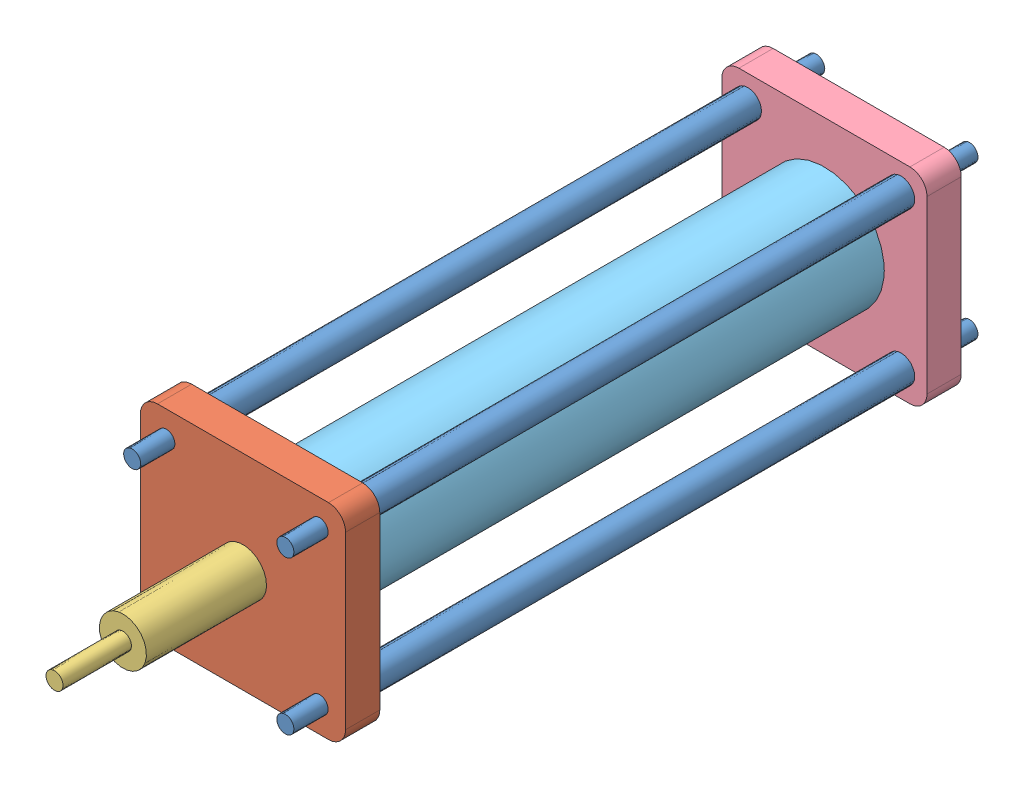
SolidWorks assembly E2_S4_AVA_E, configuration Default. Lengths in mm.
Overall size (76.2 76.2 311.28).
8 component instances, 5 part files, 16 mates.
Components (placement in the parent):
- E2_S4_AVA_P1-1: E2_S4_AVA_P1 [Default] at (10.7878 43.6934 193.1058) size (10.16 10.16 254)
- E2_S4_AVA_P2-1: E2_S4_AVA_P2 [Default] at (-17.6602 15.2454 294.7058) size (76.2 76.2 12.7)
- E2_S4_AVA_P3-1: E2_S4_AVA_P3 [Default] at (-17.6602 15.2454 136.0836) x (0.346747 0.937959 0) z (0 0 1) size (41.25 41.25 241.3)
- E2_S4_AVA_P4-1: E2_S4_AVA_P4 [Default] at (-17.6602 15.2454 78.8058) size (76.2 76.2 12.7)
- E2_S4_AVA_P5-1: E2_S4_AVA_P5 [Default] at (-17.6602 15.2454 91.5058) size (44.45 44.45 203.2)
- E2_S4_AVA_P1-2: E2_S4_AVA_P1 [Default] at (-46.1082 43.6934 193.1058) size (10.16 10.16 254)
- E2_S4_AVA_P1-3: E2_S4_AVA_P1 [Default] at (10.7878 -13.2026 193.1058) size (10.16 10.16 254)
- E2_S4_AVA_P1-4: E2_S4_AVA_P1 [Default] at (-46.1082 -13.2026 193.1058) size (10.16 10.16 254)
Mates (geometry in assembly coordinates):
- Concentric1: concentric aligned: cylinder of E2_S4_AVA_P1-1 through (10.7878 43.6934 320.1058) axis (0 0 -1) radius 3.175; cylinder of E2_S4_AVA_P2-1 through (10.7878 43.6934 307.4058) axis (0 0 -1) radius 3.175
- Coincident1: coincident anti-aligned: plane of E2_S4_AVA_P1-1 through (10.7878 43.6934 294.7058) normal (0 0 1); plane of E2_S4_AVA_P2-1 through (-49.4102 -16.5046 294.7058) normal (0 0 -1)
- Concentric2: concentric aligned: cylinder of E2_S4_AVA_P2-1 through (-46.1082 43.6934 307.4058) axis (0 0 -1) radius 3.175; cylinder of E2_S4_AVA_P1-2 through (-46.1082 43.6934 320.1058) axis (0 0 -1) radius 3.175
- Coincident2: coincident anti-aligned: plane of E2_S4_AVA_P2-1 through (-49.4102 -16.5046 294.7058) normal (0 0 -1); plane of E2_S4_AVA_P1-2 through (-46.1082 43.6934 294.7058) normal (0 0 1)
- Concentric3: concentric aligned: cylinder of E2_S4_AVA_P2-1 through (10.7878 -13.2026 307.4058) axis (0 0 -1) radius 3.175; cylinder of E2_S4_AVA_P1-3 through (10.7878 -13.2026 320.1058) axis (0 0 -1) radius 3.175
- Coincident3: coincident anti-aligned: plane of E2_S4_AVA_P2-1 through (-49.4102 -16.5046 294.7058) normal (0 0 -1); plane of E2_S4_AVA_P1-3 through (10.7878 -13.2026 294.7058) normal (0 0 1)
- Concentric4: concentric aligned: cylinder of E2_S4_AVA_P2-1 through (-46.1082 -13.2026 307.4058) axis (0 0 -1) radius 3.175; cylinder of E2_S4_AVA_P1-4 through (-46.1082 -13.2026 320.1058) axis (0 0 -1) radius 3.175
- Coincident4: coincident anti-aligned: plane of E2_S4_AVA_P2-1 through (-49.4102 -16.5046 294.7058) normal (0 0 -1); plane of E2_S4_AVA_P1-4 through (-46.1082 -13.2026 294.7058) normal (0 0 1)
- Concentric5: concentric anti-aligned: cylinder of E2_S4_AVA_P1-1 through (10.7878 43.6934 66.1058) axis (0 0 1) radius 3.175; cylinder of E2_S4_AVA_P4-1 through (10.7878 43.6934 91.5058) axis (0 0 -1) radius 3.175
- Concentric6: concentric anti-aligned: cylinder of E2_S4_AVA_P4-1 through (-46.1082 43.6934 91.5058) axis (0 0 -1) radius 3.175; cylinder of E2_S4_AVA_P1-2 through (-46.1082 43.6934 66.1058) axis (0 0 1) radius 3.175
- Concentric7: concentric anti-aligned: cylinder of E2_S4_AVA_P4-1 through (-46.1082 -13.2026 91.5058) axis (0 0 -1) radius 3.175; cylinder of E2_S4_AVA_P1-4 through (-46.1082 -13.2026 66.1058) axis (0 0 1) radius 3.175
- Concentric8: concentric anti-aligned: cylinder of E2_S4_AVA_P4-1 through (10.7878 -13.2026 91.5058) axis (0 0 -1) radius 3.175; cylinder of E2_S4_AVA_P1-3 through (10.7878 -13.2026 66.1058) axis (0 0 1) radius 3.175
- Coincident5: coincident anti-aligned: plane of E2_S4_AVA_P4-1 through (-49.4102 -16.5046 91.5058) normal (0 0 1); plane of E2_S4_AVA_P1-4 through (-46.1082 -13.2026 91.5058) normal (0 0 -1)
- Concentric9: concentric aligned: cylinder of E2_S4_AVA_P2-1 through (-17.6602 15.2454 307.4058) axis (0 0 -1) radius 8.7312; cylinder of E2_S4_AVA_P5-1 through (-17.6602 15.2454 294.7058) axis (0 0 -1) radius 22.225
- Coincident6: coincident anti-aligned: plane of E2_S4_AVA_P4-1 through (-49.4102 -16.5046 91.5058) normal (0 0 1); plane of E2_S4_AVA_P5-1 through (-17.6602 15.2454 91.5058) normal (0 0 -1)
- Concentric10: concentric aligned: cylinder of E2_S4_AVA_P2-1 through (-17.6602 15.2454 307.4058) axis (0 0 -1) radius 8.7312; cylinder of E2_S4_AVA_P3-1 through (-17.6602 15.2454 351.9836) axis (0 0 -1) radius 8.7312
